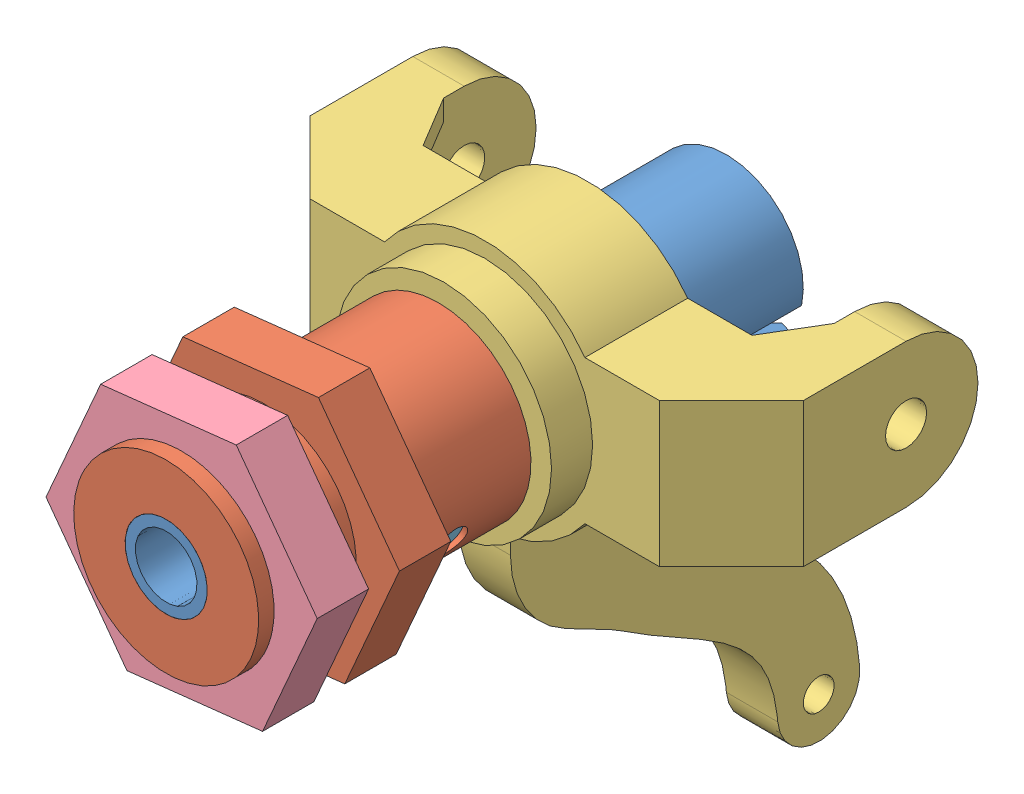
SolidWorks assembly Wheel_coupler, configuration Default. Lengths in mm.
Overall size (48 60.77 65).
7 component instances, 7 part files, 17 mates.
Components (placement in the parent):
- Wheel_shaft-1: Wheel_shaft [Default] x (-0.916276 0.400546 0) z (0 0 1) size (15 15 54.5)
- Wheel_coupler_1-1: Wheel_coupler_1 [Default] x (0.400546 0.916276 0) z (-0.916276 0.400546 0) size (26.56 27 23)
- Wheel_coupler_3-1: Wheel_coupler_3 [Default] at (0 0 -37) x (1 0 0) z (0 1 0) size (48 38 56)
- Wheel_coupler_2-1: Wheel_coupler_2 [Default] at (0 0 -6.5) x (0.400546 0.916276 0) z (0.916276 -0.400546 0) size (26.56 5 23)
- Wheel_pin-1: Wheel_pin [Default] at (7.7883 -3.4046 -19.5) x (0.147795 0.338092 0.929436) z (-0.372282 -0.85162 0.368984) size (3 17 3)
- 6701zz-1: 6701zz [Default] at (0 0 -39.0061) x (0 0 -1) z (1 0 0) size (3.99 18.01 18.01)
- 625zz-1: 625zz [Default] at (0 0 -27) x (0 0 -1) z (0.968358 -0.249564 0) size (5.11 16 16)
Mates (geometry in assembly coordinates):
- Concentric6: concentric anti-aligned: cylinder of Wheel_shaft-1 through (0 0 0) axis (0 0 1) radius 4; cylinder of Wheel_coupler_3-1 through (0 0 -33) axis (0 0 -1) radius 7
- Coincident3: coincident anti-aligned: plane of Wheel_shaft-1 through (-2.4033 -5.4977 -41) normal (0 0 1); plane of Wheel_coupler_3-1 through (0 0 -41) normal (0 0 -1)
- Concentric7: concentric anti-aligned: cylinder of Wheel_shaft-1 through (6.8721 -3.0041 -19.5) axis (-0.916276 0.400546 0) radius 1.5; cylinder of Wheel_pin-1 through (-7.7883 3.4046 -19.5) axis (0.916276 -0.400546 0) radius 1.5
- Concentric10: concentric aligned: cylinder of Wheel_shaft-1 through (0 0 0) axis (0 0 1) radius 4; cylinder of Wheel_coupler_1-1 through (0 0 -27) axis (0 0 1) radius 4
- Concentric11: concentric anti-aligned: cylinder of Wheel_coupler_1-1 through (8.2465 -3.6049 -19.5) axis (-0.916276 0.400546 0) radius 1.5; cylinder of Wheel_pin-1 through (-7.7883 3.4046 -19.5) axis (0.916276 -0.400546 0) radius 1.5
- Distance1: distance = 3 mm aligned: plane of Wheel_coupler_1-1 through (-13.1966 -1.4774 -9.5) normal (-0.916276 0.400546 0); plane of Wheel_pin-1 through (-7.7883 3.4046 -19.5) normal (-0.916276 0.400546 0)
- Concentric12: concentric anti-aligned: cylinder of Wheel_coupler_1-1 through (0 0 -27) axis (0 0 1) radius 9; cylinder of Wheel_coupler_2-1 through (0 0 -1.5) axis (0 0 -1) radius 9
- Parallel4: parallel aligned: plane of Wheel_coupler_1-1 through (-7.8777 10.6899 -9.5) normal (-0.111255 0.993792 0); plane of Wheel_coupler_2-1 through (5.3189 12.1673 -1.5) normal (-0.111255 0.993792 0)
- Distance2: distance = 3 mm anti-aligned: plane of Wheel_coupler_2-1 through (0 0 -6.5) normal (0 0 -1); plane of Wheel_coupler_1-1 through (0 0 -9.5) normal (0 0 1)
- Concentric13: concentric aligned: cylinder of Wheel_coupler_3-1 through (0 0 -41) axis (0 0 1) radius 9; cylinder of ? through (0 0 -36.8006) axis (0 0 1) radius 9.0043
- Coincident4: coincident anti-aligned: plane of Wheel_coupler_3-1 through (0 0 -37) normal (0 0 -1); plane of ? through (0 0 -37) normal (0 0 1)
- Concentric14: concentric aligned: cylinder of Wheel_coupler_3-1 through (0 0 -31) axis (0 0 -1) radius 8; cylinder of ? through (0 0 -77) axis (0 0 -1) radius 8
- Coincident5: coincident aligned: plane of Wheel_coupler_3-1 through (0 0 -27) normal (0 0 1); plane of ? through (0 7.7 -27) normal (0 0 1)
- Concentric15: concentric aligned: cylinder of Wheel_coupler_3-1 through (0 0 -41) axis (0 0 1) radius 9; cylinder of 6701zz-1 through (0 0 -36.8128) axis (0 0 1) radius 9.0043
- Coincident6: coincident aligned: plane of Wheel_coupler_3-1 through (0 0 -41) normal (0 0 -1); plane of 6701zz-1 through (0 0 -41) normal (0 0 -1)
- Concentric16: concentric aligned: cylinder of Wheel_coupler_3-1 through (0 0 -31) axis (0 0 -1) radius 8; cylinder of 625zz-1 through (0 0 -77) axis (0 0 -1) radius 8
- Coincident7: coincident aligned: plane of Wheel_coupler_3-1 through (0 0 -27) normal (0 0 1); plane of 625zz-1 through (1.9216 7.4564 -27) normal (0 0 1)
